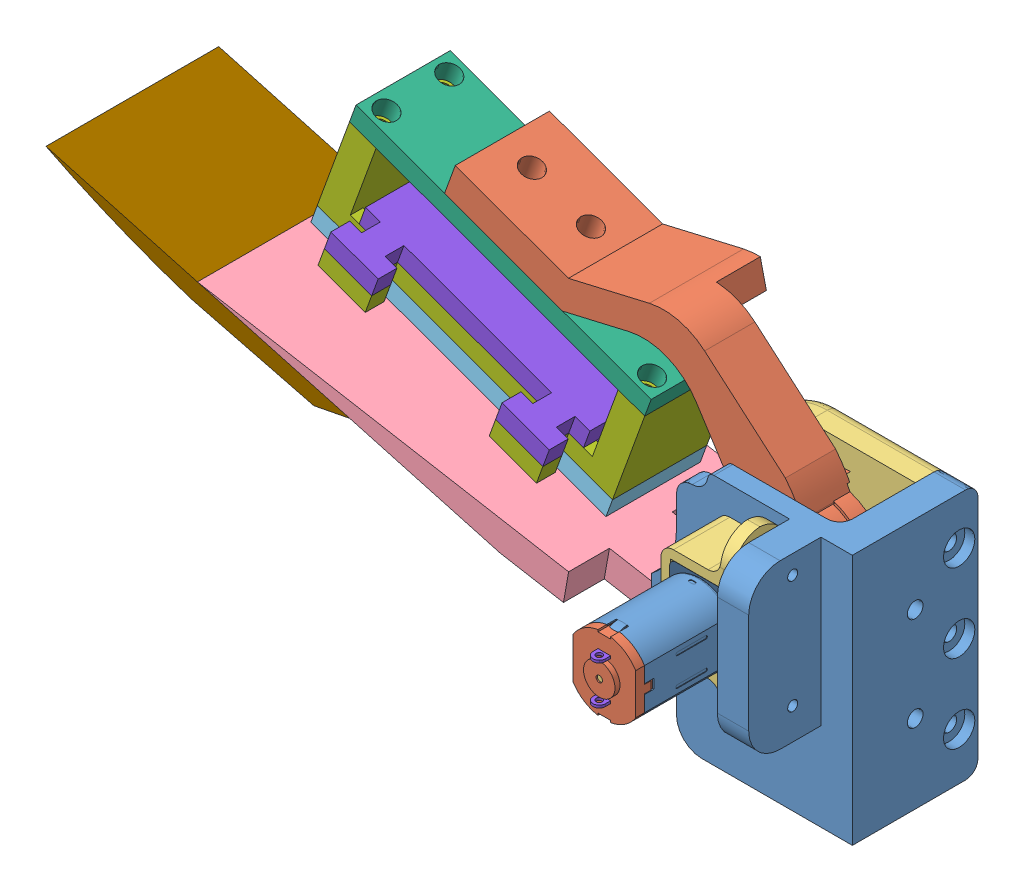
SolidWorks assembly copy_Variable_Friction_Gripper, configuration 기본. Lengths in mm.
Overall size (127.27 66.3 52.21).
44 component instances, 41 part files, 29 mates.
Components (placement in the parent):
- copy_vfg_part_1-1: copy_vfg_part_1 [기본] at (-119.2345 24.8872 4.25) size (32.32 40 31.5)
- copy_vfg_part_2-1: copy_vfg_part_2 [기본] at (-117.6058 25.1236 -7.9036) x (-0.34202 -0.939693 0) z (0 0 -1) size (27.85 68.5 15)
- copy_vfg_part_3-1: copy_vfg_part_3 [기본] at (-121.2345 16.8872 -15.75) x (0 -1 0) z (0 0 -1) size (40 27 5)
- copy_vfg_part_4-1: copy_vfg_part_4 [기본] at (-119.7345 7.5872 -0.75) x (-1 0 0) z (0 0 1) size (92.76 23.36 27.5)
- vfg_part_5-2: vfg_part_5 [기본] at (-168.5669 29.8376 -7.4036) x (0 0 -1) z (0.34202 0.939693 0) size (15 50 3)
- vfg_part_6-1: vfg_part_6 [기본] at (-162.4105 46.752 -7.4036) x (0 0 1) z (-0.34202 -0.939693 0) size (15 50 3)
- vfg_part_7-1: vfg_part_7 [기본] at (-163.4366 43.933 -7.4036) x (0 0 1) z (0.34202 0.939693 0) size (27 50 15)
- vfg_part_8-1: vfg_part_8 [기본] at (-167.5408 32.6566 -7.4036) x (0 0 -1) z (0.34202 0.939693 0) size (27 38 12)
- vfg_part_9-1: vfg_part_9 [기본] at (-186.9631 16.1459 -8) x (0 0 -1) z (0.939824 -0.34166 0) size (27.5 5.12 50)
- Motor.IGS-1: Motor.IGS [기본] at (-117.8241 24.8872 28.65) x (0 1 0) z (-1 0 0) size (12.54 36.22 10.97)
  - Engrenagem reta1.stp.IGS-1: Engrenagem reta1.stp.IGS [기본] at (0 16.35 0) x (-0.429617 0 0.903011) z (0 1 0) size (2.8 2.81 1.26)
  - Engrenagem reta2.stp.IGS-1: Engrenagem reta2.stp.IGS [기본] at (0 16.35 3) x (-0.471104 0 -0.882078) z (0 1 0) size (3.6 3.61 0.52)
  - Engrenagem reta1_1.stp.IGS-1: Engrenagem reta1_1.stp.IGS [기본] at (0 16.85 3) x (-0.277142 0 -0.960829) z (0 1 0) size (1.92 1.93 1.51)
  - Engrenagem reta2_1.stp.IGS-1: Engrenagem reta2_1.stp.IGS [기본] at (3.0146 18.35 1.9633) x (0.883421 0 0.46858) z (0 -1 0) size (4.79 4.79 0.51)
  - Engrenagem reta1_2.stp.IGS-1: Engrenagem reta1_2.stp.IGS [기본] at (3.0146 18.35 1.9633) x (-0.985151 0 -0.171692) z (0 1 0) size (1.99 1.99 2.51)
  - Engrenagem reta2_2.stp.IGS-1: Engrenagem reta2_2.stp.IGS [기본] at (0 19.55 0) x (-0.718769 0 0.695249) z (0 1 0) size (5.59 5.59 0.52)
  - Engrenagem reta1_3.stp.IGS-1: Engrenagem reta1_3.stp.IGS [기본] at (0 20.05 0) x (-0.261212 0 0.965281) z (0 1 0) size (1.99 1.99 1.26)
  - Engrenagem reta2_3.stp.IGS-1: Engrenagem reta2_3.stp.IGS [기본] at (-3.0146 21.3 -1.9633) x (-0.981768 0 0.190082) z (0 -1 0) size (5.59 5.59 0.52)
  - Engrenagem reta1_4.stp.IGS-1: Engrenagem reta1_4.stp.IGS [기본] at (-3.0146 21.4 -1.9633) x (-0.349472 0 0.936947) z (0 1 0) size (1.99 1.99 1.76)
  - Engrenagem reta2_4.stp.IGS-1: Engrenagem reta2_4.stp.IGS [기본] at (0 23.45 0) x (0.007994 0 0.999968) z (0 -1 0) size (5.59 5.59 1.71)
  - Base.stp.IGS-1: Base.stp.IGS [기본] at origin size (11.84 5.21 10.01)
  - Rotor.stp.IGS-1: Rotor.stp.IGS [기본] at (0 18 0) x (-0.799859 0 0.600187) z (0.600187 0 0.799859) size (1.61 18.61 1.01)
  - Apoio Contato.stp.IGS-1: Apoio Contato.stp.IGS [기본] at (0 2.38 0) x (0.383204 0 -0.923664) z (0.923664 0 0.383204) size (1.84 0.15 1.83)
  - Contato.stp.IGS-1: Contato.stp.IGS [기본] at (0 5 0) x (-0.999891 0 -0.014787) z (0.014787 0 -0.999891) size (6.63 3.18 6.59)
  - Suporte Contato.stp.IGS-1: Suporte Contato.stp.IGS [기본] at (0 5.7 0) x (0.518288 0 -0.855206) z (0.855206 0 0.518288) size (2 3.01 1.81)
  - Im_X_E3s.stp.IGS-1: Im_X_E3s.stp.IGS [기본] at (0 5.7 0) x (0.999997 0 -0.002497) z (0.002497 0 0.999997) size (11.56 8.51 9.63)
  - Terminais.stp.IGS-1: Terminais.stp.IGS [기본] at (-3.1 2.45 0) x (-1 0 0) z (0 0 1) size (0.42 4.27 2.02)
  - Terminais.stp.IGS-2: Terminais.stp.IGS [기본] at (3.1 2.45 0) x (1 0 0) z (0 0 -1) size (0.42 4.27 2.02)
  - Escovas.stp.IGS-1: Escovas.stp.IGS [기본] at (0 1.5101 0) size (6.45 2.03 7.34)
  - Chapa Inferior.stp.IGS-1: Chapa Inferior.stp.IGS [기본] at (0 15.4 0) x (1 0 0) z (0 0 1) size (12.05 0.83 10.05)
  - Chapa Intermedi_X_E1ria.stp.IGS-1: Chapa Intermedi_X_E1ria.stp.IGS [기본] at (0 18.6 0) x (1 0 0) z (0 0 1) size (12.05 3.61 10.05)
  - Chapa Superior.stp.IGS-1: Chapa Superior.stp.IGS [기본] at (0 23.6 0) x (1 0 0) z (0 0 1) size (12.03 6.11 10.05)
  - Eixo Maior - Engrenagem.stp.IGS-1: Eixo Maior - Engrenagem.stp.IGS [기본] at (3.0146 24.3 1.9633) x (-1 0 -0.000674) z (-0.000674 0 1) size (0.93 8.82 0.92)
  - Eixo Menor - Engrenagem.stp.IGS-1: Eixo Menor - Engrenagem.stp.IGS [기본] at (-3.0146 18.7 -1.9633) x (0.670284 0 0.742105) z (-0.742105 0 0.670284) size (0.93 5.62 0.92)
  - Parafuso.stp.IGS-1: Parafuso.stp.IGS [기본] at (3.8014 14.4 -2.7994) x (-0.923373 0 -0.383904) z (0.383904 0 -0.923373) size (2.51 10.02 2.51)
  - Parafuso.stp.IGS-2: Parafuso.stp.IGS [기본] at (-3.8014 14.4 2.7994) x (0.953489 0 -0.301427) z (0.301427 0 0.953489) size (2.51 10.02 2.51)
  - Suporte Bobinas.stp.IGS-1: Suporte Bobinas.stp.IGS [기본] at (0 13.2 0) x (0.518288 0 -0.855206) z (0.855206 0 0.518288) size (8.04 8.51 7.87)
  - Eixo Menor - Engrenagem_1.stp.IGS-1: Eixo Menor - Engrenagem_1.stp.IGS [기본] at (0 15.5 3) x (0.739249 0 0.673433) z (-0.673433 0 0.739249) size (0.93 3.82 0.92)
  - Eixo - Encaixe D.stp.IGS-1: Eixo - Encaixe D.stp.IGS [기본] at (0 23.6 0) x (0.341465 0 -0.939895) z (0.939895 0 0.341465) size (4.53 16.01 3.04)
  - Carca_X_E7a.stp.IGS-1: Carca_X_E7a.stp.IGS [기본] at (-0.0269 14.9 -0.0079) x (1 0 0) z (0 0 1) size (12.47 14.46 10.02)
- polulu_mounting_hub-1: polulu_mounting_hub [기본] at (-117.6058 25.1236 -4.75) x (-0.34202 -0.939693 0) z (0 0 1) size (17.5 17.5 5)
- Pololu_bracket-1: Pololu_bracket [Domyślna] at (-112.7345 24.0253 9.2359) x (0 -1 0) z (-1 0 0) size (26.59 11.5 11.5)
- 3mmx40mm_dowel_pin-1: 3mmx40mm_dowel_pin [기본] at (-188.3868 33.8589 -7.4036) x (-0.059751 -0.164165 0.984622) z (0.939693 -0.34202 0) size (3 3 40)
- 8pc_623ZZ-1: 8pc_623ZZ [기본] at (-154.5955 21.5599 -7.4036) x (-0.294254 -0.808457 0.509716) z (-0.939693 0.34202 0) size (10 10 32)
Mates (geometry in assembly coordinates):
- 동심1: concentric aligned: cylinder of copy_vfg_part_a-1 through (-102.7345 4.3872 -12.75) axis (1 0 0) radius 2.5; cylinder of copy_vfg_part_c-1 through (-107.7345 4.3872 -12.75) axis (1 0 0) radius 0.8
- 동심2: concentric aligned: cylinder of copy_vfg_part_a-1 through (-102.7345 29.3872 -12.75) axis (1 0 0) radius 2.5; cylinder of copy_vfg_part_c-1 through (-107.7345 29.3872 -12.75) axis (1 0 0) radius 0.8
- 일치1: coincident anti-aligned: plane of copy_vfg_part_a-1 through (-107.7345 36.8872 -15.75) normal (-1 0 0); plane of copy_vfg_part_c-1 through (-107.7345 36.8872 -10.75) normal (1 0 0)
- 동심3: concentric aligned: cylinder of copy_vfg_part_c-1 through (-123.7345 7.5872 -15.75) axis (0 0 -1) radius 1.7; cylinder of copy_vfg_part_d-1 through (-123.7345 7.5872 -10.75) axis (0 0 -1) radius 1.25
- 동심4: concentric aligned: cylinder of copy_vfg_part_c-1 through (-119.7345 3.5872 -15.75) axis (0 0 -1) radius 1.7; cylinder of copy_vfg_part_d-1 through (-119.7345 3.5872 -10.75) axis (0 0 -1) radius 1.25
- 일치2: coincident anti-aligned: plane of copy_vfg_part_c-1 through (-121.2345 16.8872 -10.75) normal (0 0 1); plane of copy_vfg_part_d-1 through (-119.7345 7.5872 -10.75) normal (0 0 -1)
- 일치3: coincident anti-aligned: plane of copy_vfg_part_a-1 through (-112.7345 29.8872 1.25) normal (-1 0 0); plane of Pololu micro-1 through (-112.7345 24.0253 9.2359) normal (1 0 0)
- 동심5: concentric aligned: cylinder of copy_vfg_part_2-1 through (-117.6058 25.1236 20.5522) axis (0 0 -1) radius 9; cylinder of polulu_mounting_hub-1 through (-117.6058 25.1236 0.25) axis (0 0 -1) radius 8.75
- 동심6: concentric anti-aligned: cylinder of copy_vfg_part_2-1 through (-111.6388 22.9517 -9.9036) axis (0 0 -1) radius 1.7; cylinder of polulu_mounting_hub-1 through (-111.6388 22.9517 0.25) axis (0 0 1) radius 1.25
- 동심7: concentric anti-aligned: cylinder of copy_vfg_part_2-1 through (-165.3989 53.1606 -7.4036) axis (0.34202 0.939693 0) radius 1.7; cylinder of vfg_part_6-1 through (-168.135 45.6431 -7.4036) axis (-0.34202 -0.939693 0) radius 1.25
- 동심8: concentric anti-aligned: cylinder of copy_vfg_part_2-1 through (-156.0019 49.7404 -7.4036) axis (0.34202 0.939693 0) radius 1.7; cylinder of vfg_part_6-1 through (-158.7381 42.2229 -7.4036) axis (-0.34202 -0.939693 0) radius 1.25
- 일치4: coincident anti-aligned: plane of copy_vfg_part_2-1 through (-153.0136 43.3318 0.0964) normal (-0.34202 -0.939693 0); plane of vfg_part_6-1 through (-162.4105 46.752 -7.4036) normal (0.34202 0.939693 0)
- 동심9: concentric anti-aligned: cylinder of vfg_part_7-1 through (-184.5796 51.6284 -12.4036) axis (0.34202 0.939693 0) radius 1.25; cylinder of vfg_part_6-1 through (-184.5796 51.6284 -12.4036) axis (-0.34202 -0.939693 0) radius 1.7
- 동심10: concentric anti-aligned: cylinder of vfg_part_6-1 through (-184.5796 51.6284 -2.4036) axis (-0.34202 -0.939693 0) radius 1.7; cylinder of vfg_part_7-1 through (-184.5796 51.6284 -2.4036) axis (0.34202 0.939693 0) radius 1.25
- 일치5: coincident anti-aligned: plane of vfg_part_7-1 through (-139.9442 35.3824 6.0974) normal (0.34202 0.939693 0); plane of vfg_part_6-1 through (-163.4366 43.933 -7.4036) normal (-0.34202 -0.939693 0)
- 일치6: coincident anti-aligned: plane of vfg_part_8-1 through (-167.5408 32.6566 -7.4036) normal (-0.34202 -0.939693 0); plane of vfg_part_7-1 through (-167.5408 32.6566 -7.4036) normal (0.34202 0.939693 0)
- 일치7: coincident aligned: plane of vfg_part_7-1 through (-184.9251 38.984 6.0964) normal (0 0 1); plane of vfg_part_8-1 through (-183.8991 41.8031 6.0964) normal (0 0 1)
- 일치8: coincident aligned: plane of vfg_part_7-1 through (-184.9251 38.984 3.0964) normal (-0.939693 0.34202 0); plane of vfg_part_8-1 through (-183.8991 41.8031 3.0964) normal (-0.939693 0.34202 0)
- 일치9: coincident anti-aligned: plane of vfg_part_5-2 through (-168.5669 29.8376 -7.4036) normal (0.34202 0.939693 0); plane of vfg_part_7-1 through (-168.5669 29.8376 -7.4036) normal (-0.34202 -0.939693 0)
- 일치10: coincident aligned: plane of vfg_part_5-2 through (-193.0852 35.569 0.0964) normal (0 0 1); plane of vfg_part_7-1 through (-138.9182 38.2015 0.0964) normal (0 0 1)
- 일치11: coincident aligned: plane of vfg_part_5-2 through (-193.0852 35.569 -14.9036) normal (-0.939693 0.34202 0); plane of vfg_part_7-1 through (-185.9028 55.3025 -14.9036) normal (-0.939693 0.34202 0)
- 동심11: concentric aligned: cylinder of vfg_part_8-1 through (-187.4471 33.5169 -7.4036) axis (-0.939693 0.34202 0) radius 1.5; cylinder of 3mmx40mm_dowel_pin-1 through (-150.7991 20.1781 -7.4036) axis (-0.939693 0.34202 0) radius 1.5
- 동심12: concentric anti-aligned: cylinder of 8pc_623ZZ-1 through (-184.6657 32.5045 -7.4036) axis (0.939693 -0.34202 0) radius 5; cylinder of 3mmx40mm_dowel_pin-1 through (-150.7991 20.1781 -7.4036) axis (-0.939693 0.34202 0) radius 1.5
- 동심13: concentric anti-aligned: cylinder of copy_vfg_part_2-1 through (-165.3989 53.1606 -7.4036) axis (0.34202 0.939693 0) radius 1.7; cylinder of vfg_part_6-1 through (-168.135 45.6431 -7.4036) axis (-0.34202 -0.939693 0) radius 1.25
- 동심14: concentric anti-aligned: cylinder of copy_vfg_part_2-1 through (-159.0947 48.8991 -16.1523) axis (0.34202 0.939693 0) radius 1.7; cylinder of vfg_part_6-1 through (-161.8309 41.3815 -16.1523) axis (-0.34202 -0.939693 0) radius 1.25
- 거리1: distance = 1 mm aligned: plane of 3mmx40mm_dowel_pin-1 through (-188.3868 33.8589 -7.4036) normal (-0.939693 0.34202 0); plane of vfg_part_8-1 through (-184.3689 41.9741 0.0964) normal (-0.939693 0.34202 0)
- 일치13: coincident anti-aligned: plane of copy_vfg_part_4-1 through (-205.4935 23.9431 5.75) normal (-0.265752 -0.964041 0); plane of vfg_part_9-1 through (-229.5945 30.5869 -21.75) normal (0.265752 0.964041 0)
- 일치14: coincident aligned: plane of copy_vfg_part_4-1 through (-119.7345 7.5872 5.75) normal (0 0 1); plane of vfg_part_9-1 through (-157.5333 173.4406 5.75) normal (0 0 1)
- 거리2: distance = 25 mm: line of copy_vfg_part_4-1 through (-205.4935 23.9431 -21.75) axis (0 0 1); line of vfg_part_9-1 through (-229.5945 30.5869 -21.75) axis (0 0 1)
